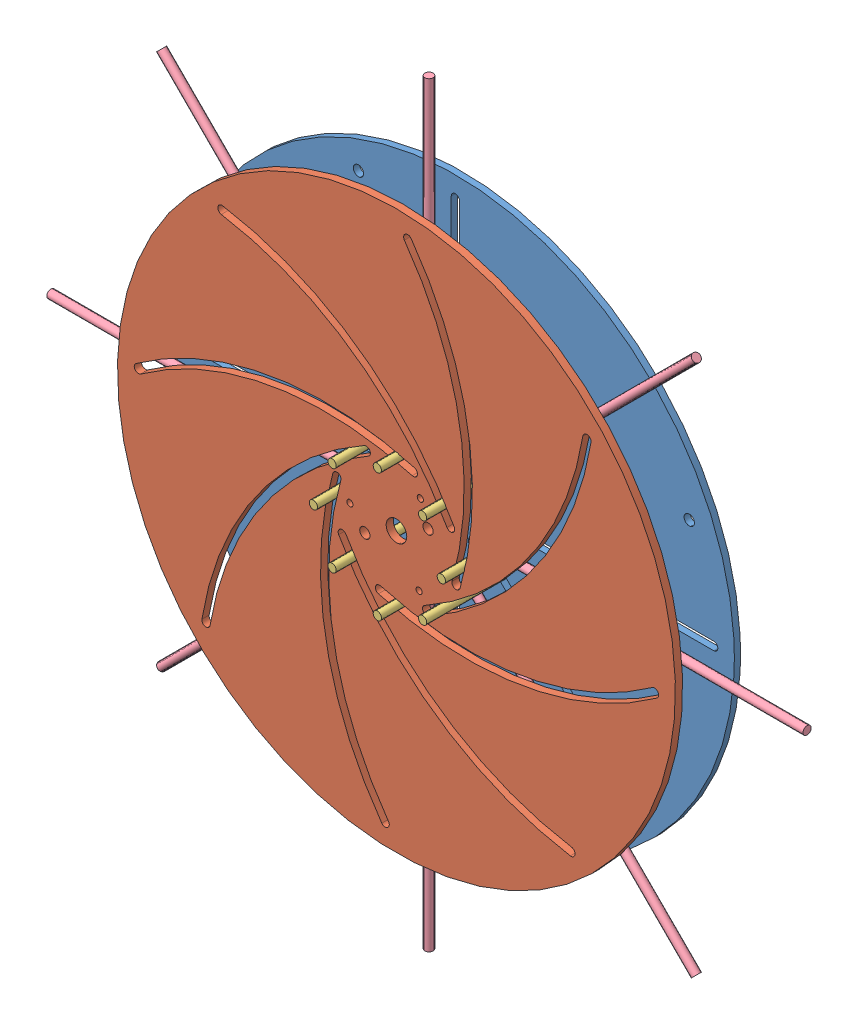
SolidWorks assembly shell-test, configuration Default. Lengths in mm.
Overall size (367.28 367.28 50).
18 component instances, 4 part files, 10 mates.
Components (placement in the parent):
- facePlate-2.0-1: facePlate-2.0 [Default] at origin size (270 270 3)
- clutchPlate-2.0-1: clutchPlate-2.0 [Default] at (0 0 29.75) x (0.87354 0.486753 0) z (0 0 1) size (270 270 3.5)
- spoke-1: spoke [Default] at (-30.9487 0 15.75) x (-0.503022 -0.864273 0) z (0 0 1) size (4 4 50)
- spoke-2: spoke [Default] at (-21.884 -21.884 15.75) x (0.255443 -0.966824 0) z (0 0 1) size (4 4 50)
- spoke-3: spoke [Default] at (0 -30.9487 15.75) x (0.864273 -0.503022 0) z (0 0 1) size (4 4 50)
- spoke-4: spoke [Default] at (21.884 -21.884 15.75) x (0.966824 0.255443 0) z (0 0 1) size (4 4 50)
- spoke-5: spoke [Default] at (30.9487 0 15.75) x (0.503022 0.864273 0) z (0 0 1) size (4 4 50)
- spoke-6: spoke [Default] at (21.884 21.884 15.75) x (-0.255443 0.966824 0) z (0 0 1) size (4 4 50)
- spoke-7: spoke [Default] at (0 30.9487 15.75) x (-0.864273 0.503022 0) z (0 0 1) size (4 4 50)
- spoke-8: spoke [Default] at (-21.884 21.884 15.75) x (-0.966824 -0.255443 0) z (0 0 1) size (4 4 50)
- shell-spoke-1: shell-spoke [Default] at (-82.9487 0 15.75) x (0 -1 0) z (-1 0 0) size (4 4 150)
- shell-spoke-2: shell-spoke [Default] at (-58.6536 -58.6536 15.75) x (0.707107 -0.707107 0) z (-0.707107 -0.707107 0) size (4 4 150)
- shell-spoke-3: shell-spoke [Default] at (0 -82.9487 15.75) x (1 0 0) z (0 -1 0) size (4 4 150)
- shell-spoke-4: shell-spoke [Default] at (58.6536 -58.6536 15.75) x (0.707107 0.707107 0) z (0.707107 -0.707107 0) size (4 4 150)
- shell-spoke-5: shell-spoke [Default] at (82.9487 0 15.75) x (0 1 0) z (1 0 0) size (4 4 150)
- shell-spoke-6: shell-spoke [Default] at (58.6536 58.6536 15.75) x (-0.707107 0.707107 0) z (0.707107 0.707107 0) size (4 4 150)
- shell-spoke-7: shell-spoke [Default] at (0 82.9487 15.75) x (-1 0 0) z (0 1 0) size (4 4 150)
- shell-spoke-8: shell-spoke [Default] at (-58.6536 58.6536 15.75) x (-0.707107 -0.707107 0) z (-0.707107 0.707107 0) size (4 4 150)
Mates (geometry in assembly coordinates):
- Coincident1: coordinate: point of facePlate-2.0-1
- Concentric1: concentric aligned: circle of facePlate-2.0-1; circle of clutchPlate-2.0-1
- Distance1: distance = 25 mm anti-aligned: plane of facePlate-2.0-1 through (0 0 3) normal (0 0 1); plane of clutchPlate-2.0-1 through (0 0 28) normal (0 0 -1)
- Slot1: slot aligned: cylinder of spoke-1 through (-30.9487 0 -9.25) axis (0 0 1) radius 2; cylinder of clutchPlate-2.0-1 through (120.234 -34.1875 28) axis (0 0 1) radius 157; cylinder of clutchPlate-2.0-1 through (-5.4631 -124.8806 28) axis (0 0 1) radius 2
- Slot2: slot anti-aligned: cylinder of spoke-1 through (-30.9487 0 -9.25) axis (0 0 1) radius 2; plane of facePlate-2.0-1 through (-30 -2 3) normal (0 1 0); cylinder of facePlate-2.0-1 through (-125 0 3) axis (0 0 -1) radius 2
- Width1: width anti-aligned: plane of clutchPlate-2.0-1 through (0 0 31.5) normal (0 0 1); plane of facePlate-2.0-1 through (0 0 0) normal (0 0 -1); plane of spoke-1 through (-30.9487 0 -9.25) normal (0 0 -1); plane of spoke-1 through (-30.9487 0 40.75) normal (0 0 1)
- Width2: width: plane of clutchPlate-2.0-1 through (0 0 31.5) normal (0 0 1); plane of facePlate-2.0-1 through (0 0 0) normal (0 0 -1); cylinder of shell-spoke-1 through (-32.9487 0 15.75) axis (-1 0 0) radius 2
- Parallel1: parallel anti-aligned: plane of facePlate-2.0-1 through (-30 -2 3) normal (0 1 0); plane of shell-spoke-1 through (-82.9487 0 15.75) normal (0 -1 0)
- Width3: width: plane of facePlate-2.0-1 through (-30 -2 3) normal (0 1 0); plane of facePlate-2.0-1 through (-30 2 3) normal (0 -1 0); cylinder of shell-spoke-1 through (-32.9487 0 15.75) axis (-1 0 0) radius 2
- Tangent2: tangent anti-aligned: cylinder of spoke-1 through (-30.9487 0 -9.25) axis (0 0 1) radius 2; plane of shell-spoke-1 through (-32.9487 0 15.75) normal (1 0 0)
